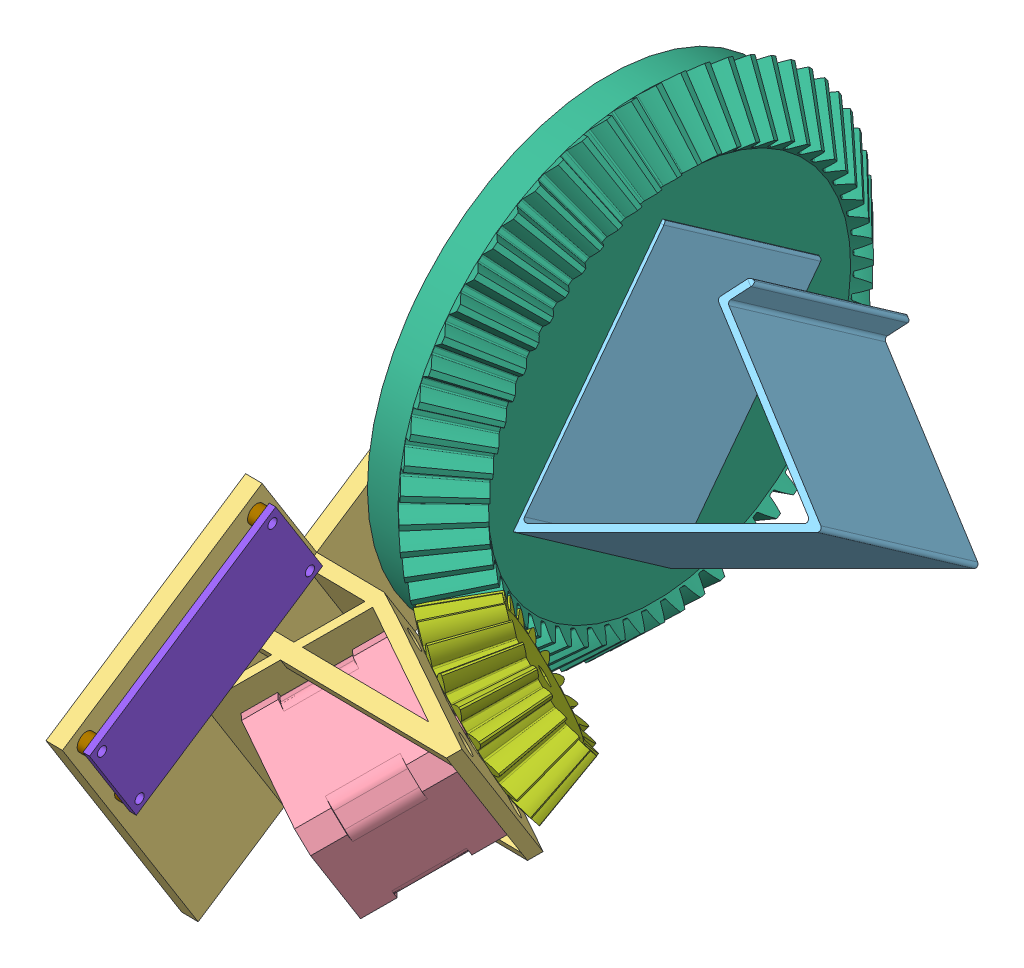
SolidWorks assembly Assem3, configuration Default. Lengths in mm.
Overall size (114.58 215.39 270.04).
12 component instances, 9 part files, 28 mates.
Components (placement in the parent):
- roulement-1: roulement [Default] at (-52.9275 41.6015 74.4913) x (0.051956 0.507096 0.860322) z (0.022673 0.860664 -0.508668) size (80 18 80)
- support_bot-1: support_bot [Default] at (-37.9516 40.9125 73.993) x (0.056623 0.836084 0.545671) z (-0.998392 0.045934 0.033219) size (100 100 27.09)
- sopport_hub_carte-1: sopport_hub_carte [Default] at (-64.6964 -0.5956 140.3674) x (-0.056623 -0.836084 -0.545671) z (0.002709 -0.546674 0.837341) size (87 66.61 125)
- moteur_pas_a_pas-1: moteur_pas_a_pas [Default] at (-38.0245 -27.9917 179.5765) x (0.8828 -0.297206 0.363777) z (0.056623 0.836084 0.545671) size (42 61.7 49)
- support_telephone-1: support_telephone [Default] at (-28.4188 51.5328 25.5973) x (-0.017829 -0.81071 0.585176) z (0.053811 0.583643 0.810226) size (77.59 73.66 65)
- plateau_top_v4-2: plateau_top_v4 [ISO - Straight bevel gear 2.5M 60GT 60PT 20PA 20FW ---60O10H50MD0.8N] at (-42.9436 41.1422 74.1591) x (0.998392 -0.045934 -0.033219) z (0.053811 0.583643 0.810226) size (29.18 153.51 153.51)
- pignon_moteur_v3.8N-2: pignon_moteur_v3.8N [ISO - Straight bevel pinion 2.5M20PT 60GT 14.5PA 20FW ---20O75H50MD0.8N] at (-17.7393 -7.9329 146.7372) x (0.466325 0.46112 -0.754923) z (0.8828 -0.297206 0.363777) size (21.95 56.2 56.2)
- PCB-1: PCB [Default] at (-52.1478 14.8145 195.1722) x (-0.002709 0.546674 -0.837341) z (0.056623 0.836084 0.545671) size (70 2 30)
- rondelle-1: rondelle [Default] at (-53.5518 42.4329 174.9918) x (-0.039832 -0.151505 -0.987654) z (0.040334 0.987389 -0.153091) size (5.5 3 5.5)
- rondelle-2: rondelle [Default] at (-54.9107 22.3669 161.8957) x (0.046989 0.998392 0.031709) z (0.031709 -0.033219 0.998945) size (5.5 3 5.5)
- rondelle-3: rondelle [Default] at (-54.7374 -12.6203 215.4855) x (0.046989 0.998392 0.031709) z (0.031709 -0.033219 0.998945) size (5.5 3 5.5)
- rondelle-4: rondelle [Default] at (-53.3784 7.4458 228.5816) x (0.046989 0.998392 0.031709) z (0.031709 -0.033219 0.998945) size (5.5 3 5.5)
Mates (geometry in assembly coordinates):
- Concentric2: concentric anti-aligned: cylinder of roulement-1 through (-34.9565 40.7747 73.8933) axis (-0.998392 0.045934 0.033219) radius 20; cylinder of support_bot-1 through (-52.9275 41.6015 74.4913) axis (0.998392 -0.045934 -0.033219) radius 19.875
- Coincident2: coincident anti-aligned: plane of roulement-1 through (-52.9275 41.6015 74.4913) normal (-0.998392 0.045934 0.033219); plane of support_bot-1 through (-52.9275 41.6015 74.4913) normal (0.998392 -0.045934 -0.033219)
- Concentric7: concentric aligned: cylinder of support_bot-1 through (-38.2742 14.0339 101.4657) axis (-0.998392 0.045934 0.033219) radius 2.5; cylinder of sopport_hub_carte-1 through (-55.2469 14.8148 102.0304) axis (-0.998392 0.045934 0.033219) radius 2.25
- Concentric8: concentric aligned: cylinder of support_bot-1 through (-37.4248 26.5752 109.6507) axis (-0.998392 0.045934 0.033219) radius 2.5; cylinder of sopport_hub_carte-1 through (-54.3975 27.356 110.2155) axis (-0.998392 0.045934 0.033219) radius 2.25
- Coincident8: coincident anti-aligned: plane of support_bot-1 through (-57.4203 41.8082 74.6408) normal (-0.998392 0.045934 0.033219); plane of sopport_hub_carte-1 through (-57.4054 38.8077 79.2366) normal (0.998392 -0.045934 -0.033219)
- Coincident9: coincident anti-aligned: plane of sopport_hub_carte-1 through (-43.8403 -64.6859 103.2344) normal (-0.466325 -0.46112 0.754923); plane of moteur_pas_a_pas-1 through (-20.3042 -10.4692 150.8894) normal (0.466325 0.46112 -0.754923)
- Coincident11: coincident anti-aligned: plane of sopport_hub_carte-1 through (-64.6964 -0.5956 140.3674) normal (-0.056623 -0.836084 -0.545671); plane of moteur_pas_a_pas-1 through (-38.0245 -27.9917 179.5765) normal (0.056623 0.836084 0.545671)
- Concentric9: concentric aligned: cylinder of roulement-1 through (-34.9565 40.7747 73.8933) axis (-0.998392 0.045934 0.033219) radius 40; cylinder of plateau_top_v4-2 through (-34.9565 40.7747 73.8933) axis (-0.998392 0.045934 0.033219) radius 40.125
- Coincident13: coincident anti-aligned: plane of roulement-1 through (-34.9565 40.7747 73.8933) normal (0.998392 -0.045934 -0.033219); plane of plateau_top_v4-2 through (-34.9565 40.7747 73.8933) normal (-0.998392 0.045934 0.033219)
- Coincident14: coincident anti-aligned: plane of support_telephone-1 through (-26.9179 89.5615 78.3284) normal (-0.998392 0.045934 0.033219); plane of plateau_top_v4-2 through (-29.3282 40.5157 73.7061) normal (0.998392 -0.045934 -0.033219)
- Coincident15: coincident anti-aligned: plane of support_telephone-1 through (-24.9211 89.4696 78.262) normal (0.053811 0.583643 0.810226); plane of plateau_top_v4-2 through (-26.9179 89.5615 78.3284) normal (-0.053811 -0.583643 -0.810226)
- Coincident16: coincident: line of support_telephone-1 through (-25.9733 88.9319 77.4849) axis (-0.053811 -0.583643 -0.810226); plane of plateau_top_v4-2 through (-30.4156 51.6247 25.6637) normal (-0.017829 -0.81071 0.585176)
- Concentric11: concentric anti-aligned: cylinder of moteur_pas_a_pas-1 through (-17.7394 -7.933 146.7373) axis (-0.466325 -0.46112 0.754923) radius 2.5; cylinder of pignon_moteur_v3.8N-2 through (-17.7394 -7.933 146.7373) axis (0.466325 0.46112 -0.754923) radius 2.75
- Parallel3: parallel anti-aligned: plane of moteur_pas_a_pas-1 through (-9.4588 -1.305 132.0574) normal (-0.056623 -0.836084 -0.545671); plane of pignon_moteur_v3.8N-2 through (-17.8699 -9.8601 145.4796) normal (0.056623 0.836084 0.545671)
- Coincident23: coincident anti-aligned: plane of moteur_pas_a_pas-1 through (-17.7394 -7.933 146.7373) normal (0.466325 0.46112 -0.754923); plane of pignon_moteur_v3.8N-2 through (-17.7394 -7.933 146.7373) normal (-0.466325 -0.46112 0.754923)
- Coincident29: coincident anti-aligned: plane of PCB-1 through (-54.1446 14.9063 195.2386) normal (-0.998392 0.045934 0.033219); plane of rondelle-1 through (-53.5518 42.4329 174.9918) normal (0.998392 -0.045934 -0.033219)
- Concentric16: concentric anti-aligned: cylinder of PCB-1 through (-52.7406 -12.7121 215.4191) axis (-0.998392 0.045934 0.033219) radius 1.5; cylinder of rondelle-3 through (-57.7326 -12.4825 215.5852) axis (0.998392 -0.045934 -0.033219) radius 2
- Concentric17: concentric anti-aligned: cylinder of PCB-1 through (-51.3816 7.3539 228.5152) axis (-0.998392 0.045934 0.033219) radius 1.5; cylinder of rondelle-4 through (-56.3736 7.5836 228.6813) axis (0.998392 -0.045934 -0.033219) radius 2
- Coincident30: coincident anti-aligned: plane of PCB-1 through (-54.1446 14.9063 195.2386) normal (-0.998392 0.045934 0.033219); plane of rondelle-4 through (-53.3784 7.4458 228.5816) normal (0.998392 -0.045934 -0.033219)
- Coincident31: coincident anti-aligned: plane of PCB-1 through (-54.1446 14.9063 195.2386) normal (-0.998392 0.045934 0.033219); plane of rondelle-3 through (-54.7374 -12.6203 215.4855) normal (0.998392 -0.045934 -0.033219)
- Coincident32: coincident anti-aligned: plane of PCB-1 through (-54.1446 14.9063 195.2386) normal (-0.998392 0.045934 0.033219); plane of rondelle-1 through (-53.5518 42.4329 174.9918) normal (0.998392 -0.045934 -0.033219)
- Coincident34: coincident anti-aligned: plane of PCB-1 through (-54.1446 14.9063 195.2386) normal (-0.998392 0.045934 0.033219); plane of rondelle-2 through (-54.9107 22.3669 161.8957) normal (0.998392 -0.045934 -0.033219)
- Concentric18: concentric anti-aligned: cylinder of PCB-1 through (-52.914 22.275 161.8292) axis (-0.998392 0.045934 0.033219) radius 1.5; cylinder of rondelle-2 through (-57.9059 22.5047 161.9953) axis (0.998392 -0.045934 -0.033219) radius 2
- Concentric19: concentric anti-aligned: cylinder of PCB-1 through (-51.555 42.3411 174.9253) axis (-0.998392 0.045934 0.033219) radius 1.5; cylinder of rondelle-1 through (-56.547 42.5707 175.0914) axis (0.998392 -0.045934 -0.033219) radius 2
- Coincident35: coincident anti-aligned: plane of sopport_hub_carte-1 through (-59.7044 -0.8252 140.2013) normal (0.998392 -0.045934 -0.033219); plane of rondelle-4 through (-56.3736 7.5836 228.6813) normal (-0.998392 0.045934 0.033219)
- Concentric20: concentric aligned: cylinder of sopport_hub_carte-1 through (-62.7245 -12.2528 215.7512) axis (0.998392 -0.045934 -0.033219) radius 1.75; cylinder of rondelle-3 through (-57.7326 -12.4825 215.5852) axis (0.998392 -0.045934 -0.033219) radius 2
- Concentric21: concentric aligned: cylinder of sopport_hub_carte-1 through (-61.3656 7.8132 228.8473) axis (0.998392 -0.045934 -0.033219) radius 1.75; cylinder of rondelle-4 through (-56.3736 7.5836 228.6813) axis (0.998392 -0.045934 -0.033219) radius 2
- Concentric22: concentric aligned: cylinder of sopport_hub_carte-1 through (-3.8778 -0.2721 161.9662) axis (0.466325 0.46112 -0.754923) radius 1.7; cylinder of moteur_pas_a_pas-1 through (-5.7431 -2.1165 164.9858) axis (0.466325 0.46112 -0.754923) radius 1.25
